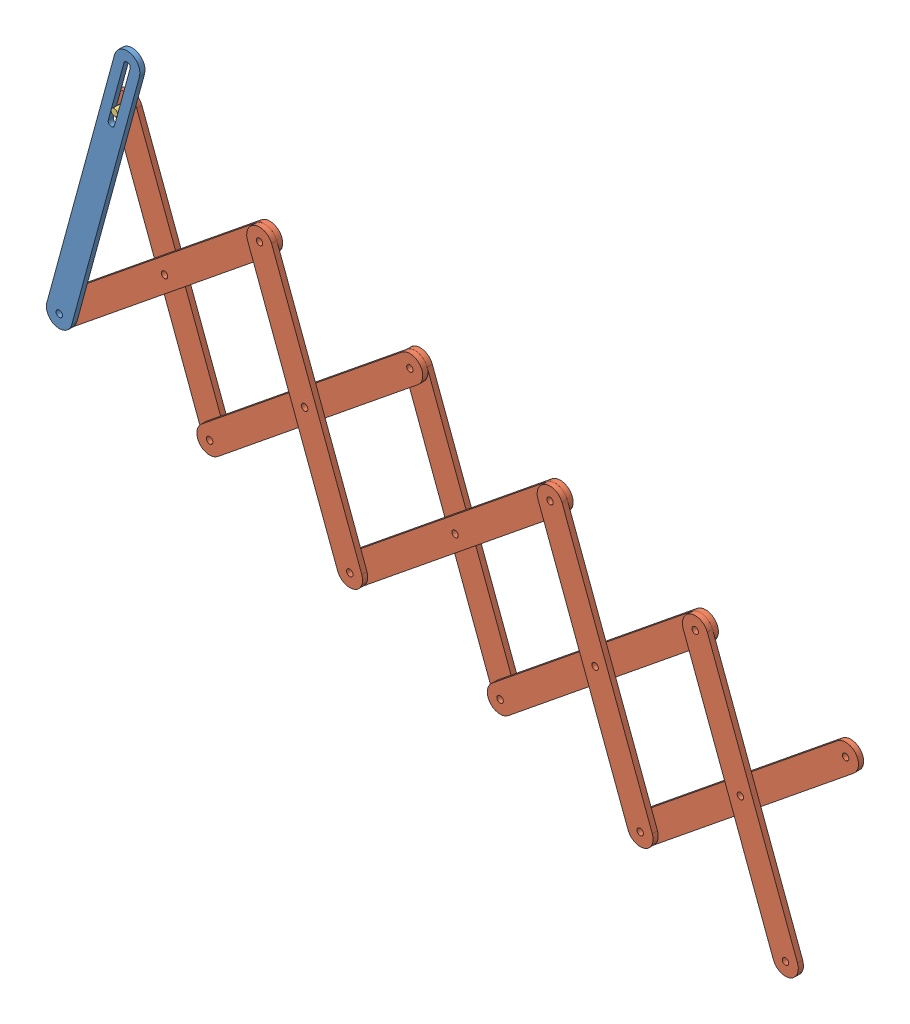
SolidWorks assembly Scissor Mechanism, configuration Default. Lengths in mm.
Overall size (3170.32 1857.69 60).
12 component instances, 3 part files, 27 mates.
Components (placement in the parent):
- Part6-1: Part6 [Default] at (-364.3601 258.0367 828.0248) x (0.262815 0.964846 0) z (0.964846 -0.262815 0) size (1100 20 100)
- part1-1: part1 [Default] at (-107.4481 90.5867 788.0248) x (0.349873 -0.936797 0) z (0 0 1) size (1100 100 20)
- part5-1: part5 [Default] at (-282.3846 558.9852 848.0248) x (1 0 0) z (0 1 0) size (25 60 25)
- part1-2: part1 [Default] at (1582.3197 -369.6896 808.0248) x (0.776639 0.629946 0) z (0 0 1) size (1100 100 20)
- part1-3: part1 [Default] at (455.8078 -62.8388 808.0248) x (0.776639 0.629946 0) z (0 0 1) size (1100 100 20)
- part1-4: part1 [Default] at (455.8078 -62.8388 828.0248) x (0.349873 -0.936797 0) z (0 0 1) size (1100 100 20)
- part1-5: part1 [Default] at (1582.3197 -369.6896 828.0248) x (0.349873 -0.936797 0) z (0 0 1) size (1100 100 20)
- part1-6: part1 [Default] at (-107.4481 90.5867 808.0248) x (0.776639 0.629946 0) z (0 0 1) size (1100 100 20)
- part1-7: part1 [Default] at (1019.0637 -216.2642 788.0248) x (0.349873 -0.936797 0) z (0 0 1) size (1100 100 20)
- part1-8: part1 [Default] at (1019.0637 -216.2642 808.0248) x (0.776639 0.629946 0) z (0 0 1) size (1100 100 20)
- part1-9: part1 [Default] at (2145.5756 -523.115 808.0248) x (0.776639 0.629946 0) z (0 0 1) size (1100 100 20)
- part1-10: part1 [Default] at (2145.5756 -523.115 828.0248) x (0.349873 -0.936797 0) z (0 0 1) size (1100 100 20)
Mates (geometry in assembly coordinates):
- Concentric1: concentric anti-aligned: cylinder of part1-1 through (-282.3846 558.9852 808.0248) axis (0 0 -1) radius 12.5; cylinder of part5-1 through (-282.3846 558.9852 788.0248) axis (0 0 1) radius 12.5
- Coincident1: coincident aligned: plane of part1-1 through (-282.3846 558.9852 788.0248) normal (0 0 -1); plane of part5-1 through (-282.3846 558.9852 788.0248) normal (0 0 -1)
- Coincident2: coincident aligned: plane of Part6-1 through (-364.3601 258.0367 848.0248) normal (0 0 1); plane of part5-1 through (-282.3846 558.9852 848.0248) normal (0 0 1)
- Tangent1: tangent anti-aligned: plane of Part6-1 through (-376.4206 261.3219 848.0248) normal (0.964846 -0.262815 0); cylinder of part5-1 through (-282.3846 558.9852 788.0248) axis (0 0 1) radius 12.5
- Concentric2: concentric aligned: cylinder of Part6-1 through (-495.7674 -224.3865 848.0248) axis (0 0 -1) radius 12.5; cylinder of part1-6 through (-495.7674 -224.3865 828.0248) axis (0 0 -1) radius 12.5
- Coincident3: coincident anti-aligned: plane of Part6-1 through (-364.3601 258.0367 828.0248) normal (0 0 -1); plane of part1-6 through (-495.7674 -224.3865 828.0248) normal (0 0 1)
- Concentric3: concentric aligned: cylinder of part1-1 through (-107.4481 90.5867 808.0248) axis (0 0 -1) radius 12.5; cylinder of part1-6 through (-107.4481 90.5867 828.0248) axis (0 0 -1) radius 12.5
- Concentric4: concentric aligned: cylinder of part1-4 through (280.8713 405.5598 848.0248) axis (0 0 -1) radius 12.5; cylinder of part1-6 through (280.8713 405.5598 828.0248) axis (0 0 -1) radius 12.5
- Coincident4: coincident anti-aligned: plane of part1-4 through (280.8713 405.5598 828.0248) normal (0 0 -1); plane of part1-6 through (-495.7674 -224.3865 828.0248) normal (0 0 1)
- Concentric5: concentric aligned: cylinder of part1-1 through (67.4885 -377.8119 808.0248) axis (0 0 -1) radius 12.5; cylinder of part1-3 through (67.4885 -377.8119 828.0248) axis (0 0 -1) radius 12.5
- Coincident5: coincident anti-aligned: plane of part1-1 through (-282.3846 558.9852 808.0248) normal (0 0 1); plane of part1-3 through (67.4885 -377.8119 808.0248) normal (0 0 -1)
- Concentric6: concentric aligned: cylinder of part1-3 through (455.8078 -62.8388 828.0248) axis (0 0 -1) radius 12.5; cylinder of part1-4 through (455.8078 -62.8388 848.0248) axis (0 0 -1) radius 12.5
- Concentric7: concentric aligned: cylinder of part1-4 through (630.7444 -531.2373 848.0248) axis (0 0 -1) radius 12.5; cylinder of part1-8 through (630.7444 -531.2373 828.0248) axis (0 0 -1) radius 12.5
- Coincident6: coincident anti-aligned: plane of part1-4 through (280.8713 405.5598 828.0248) normal (0 0 -1); plane of part1-8 through (630.7444 -531.2373 828.0248) normal (0 0 1)
- Concentric8: concentric aligned: cylinder of part1-3 through (844.1272 252.1344 828.0248) axis (0 0 -1) radius 12.5; cylinder of part1-7 through (844.1272 252.1344 808.0248) axis (0 0 -1) radius 12.5
- Coincident7: coincident anti-aligned: plane of part1-3 through (67.4885 -377.8119 808.0248) normal (0 0 -1); plane of part1-7 through (844.1272 252.1344 808.0248) normal (0 0 1)
- Concentric9: concentric aligned: cylinder of part1-7 through (1019.0637 -216.2642 808.0248) axis (0 0 -1) radius 12.5; cylinder of part1-8 through (1019.0637 -216.2642 828.0248) axis (0 0 -1) radius 12.5
- Concentric10: concentric aligned: cylinder of part1-2 through (1194.0003 -684.6627 828.0248) axis (0 0 -1) radius 12.5; cylinder of part1-7 through (1194.0003 -684.6627 808.0248) axis (0 0 -1) radius 12.5
- Concentric11: concentric aligned: cylinder of part1-5 through (1407.3831 98.709 848.0248) axis (0 0 -1) radius 12.5; cylinder of part1-8 through (1407.3831 98.709 828.0248) axis (0 0 -1) radius 12.5
- Coincident8: coincident anti-aligned: plane of part1-5 through (1407.3831 98.709 828.0248) normal (0 0 -1); plane of part1-8 through (630.7444 -531.2373 828.0248) normal (0 0 1)
- Coincident9: coincident anti-aligned: plane of part1-2 through (1194.0003 -684.6627 808.0248) normal (0 0 -1); plane of part1-7 through (844.1272 252.1344 808.0248) normal (0 0 1)
- Concentric12: concentric aligned: cylinder of part1-2 through (1582.3197 -369.6896 828.0248) axis (0 0 -1) radius 12.5; cylinder of part1-5 through (1582.3197 -369.6896 848.0248) axis (0 0 -1) radius 12.5
- Concentric13: concentric aligned: cylinder of part1-5 through (1757.2562 -838.0881 848.0248) axis (0 0 -1) radius 12.5; cylinder of part1-9 through (1757.2562 -838.0881 828.0248) axis (0 0 -1) radius 12.5
- Coincident10: coincident anti-aligned: plane of part1-5 through (1407.3831 98.709 828.0248) normal (0 0 -1); plane of part1-9 through (1757.2562 -838.0881 828.0248) normal (0 0 1)
- Concentric14: concentric aligned: cylinder of part1-2 through (1970.639 -54.7164 828.0248) axis (0 0 -1) radius 12.5; cylinder of part1-10 through (1970.639 -54.7164 808.0248) axis (0 0 -1) radius 12.5
- Concentric15: concentric aligned: cylinder of part1-9 through (2145.5756 -523.115 828.0248) axis (0 0 -1) radius 12.5; cylinder of part1-10 through (2145.5756 -523.115 808.0248) axis (0 0 -1) radius 12.5
- Coincident12: coincident anti-aligned: plane of part1-2 through (1194.0003 -684.6627 828.0248) normal (0 0 1); plane of part1-10 through (1970.639 -54.7164 828.0248) normal (0 0 -1)
